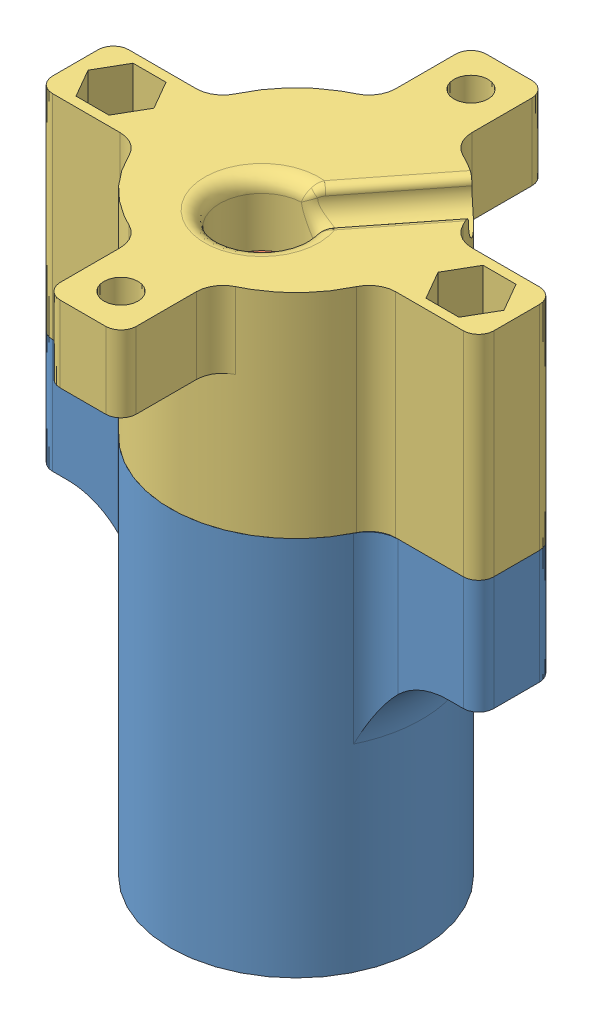
SolidWorks assembly Assem1, configuration Default. Lengths in mm.
Overall size (58 78.12 56).
3 component instances, 3 part files, 5 mates.
Components (placement in the parent):
- FrontPipe-1: FrontPipe [Default] at (-166.7087 -69.2041 101.0169) size (58 50 33)
- Sensor-1: Sensor [Default] at (-166.7087 -19.2041 101.0169) size (25.1 20.31 25.1)
- SensorBase-1: SensorBase [Default] at (-166.7087 -19.2041 101.0169) x (-1 0 0) z (0 0 -1) size (58 28.12 56)
Mates (geometry in assembly coordinates):
- Concentric2: concentric anti-aligned: cylinder of Sensor-1 through (-166.7087 1.1059 105.5169) axis (0 -1 0) radius 3; cylinder of SensorBase-1 through (-166.7087 -19.2041 105.5169) axis (0 1 0) radius 5.5
- Concentric3: concentric aligned: cylinder of Sensor-1 through (-166.7087 -0.5041 101.0169) axis (0 -1 0) radius 10.75; cylinder of SensorBase-1 through (-166.7087 8.7959 101.0169) axis (0 -1 0) radius 16.5
- Coincident2: coincident anti-aligned: plane of FrontPipe-1 through (-150.2087 -19.2041 101.0169) normal (0 1 0); plane of SensorBase-1 through (-166.7087 -19.2041 101.0169) normal (0 -1 0)
- Concentric4: concentric anti-aligned: cylinder of FrontPipe-1 through (-143.7087 -69.2041 101.0169) axis (0 1 0) radius 2.25; cylinder of SensorBase-1 through (-143.7087 8.7959 101.0169) axis (0 -1 0) radius 2.25
- Coincident3: coincident anti-aligned: plane of Sensor-1 through (-166.7087 -17.7041 101.0169) normal (0 1 0); plane of SensorBase-1 through (-166.7087 -17.7041 101.0169) normal (0 -1 0)
